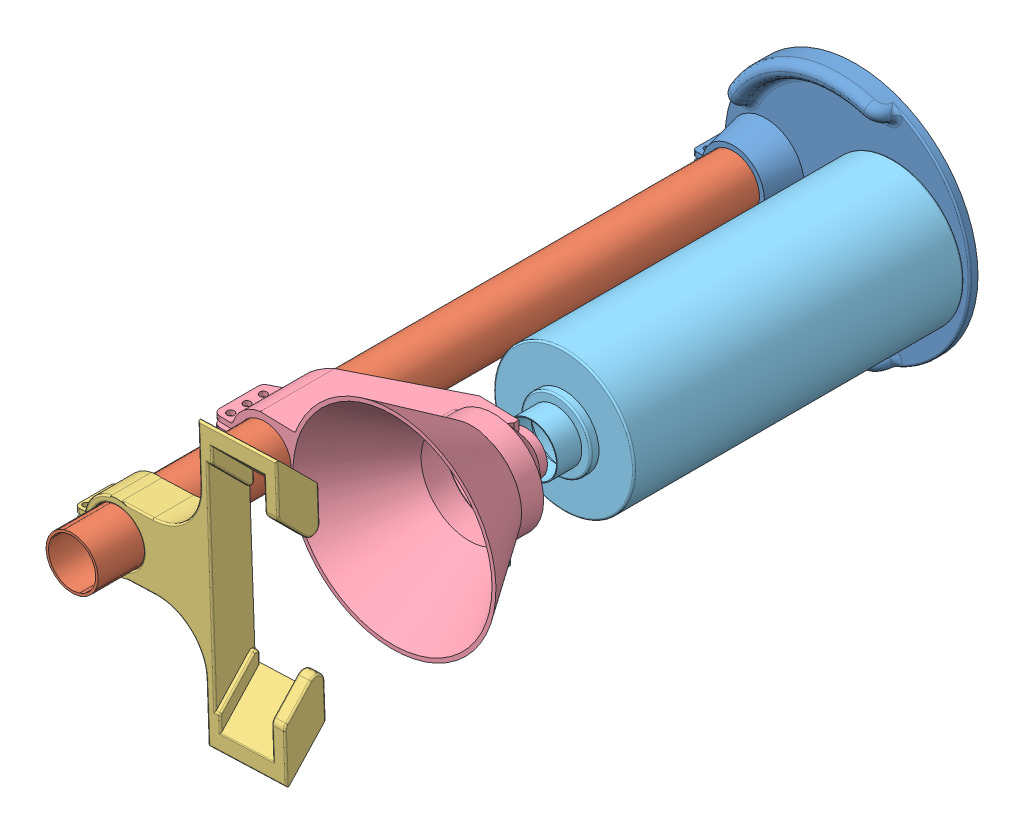
SolidWorks assembly 树脂沥干支架, configuration 默认. Lengths in mm.
Overall size (176.78 231.56 430).
6 component instances, 6 part files, 6 mates.
Components (placement in the parent):
- 底座-1: 底座 [默认] at (-38.7158 -17.6664 148.5) size (150.1 150 25.11)
- 管子-1: 管子 [默认] at (-88.7158 -17.6664 363.5) x (0.891054 -0.453896 0) z (0 0 1) size (32 32 430)
- 料槽放置-2-平-1: 料槽放置-2-平 [默认] at (-11.946 -14.8249 525.9527) x (-0.036989 0.999316 0) z (0.999316 0.036989 0) size (169.8 25.06 126.82)
- 漏斗-2-1: 漏斗-2 [默认] at (-10.3773 -19.7866 393.5703) x (-0.999634 0.027054 0) z (0.027054 0.999634 0) size (173.41 82 126.82)
- 一升瓶子-1: 一升瓶子 [默认] at (-10.3773 -19.7866 264.5) x (1 0 0) z (0 -1 0) size (86 222 86)
- 夹子2-1: 夹子2 [默认] at (-99.3405 -160.6541 304.5729) size (6.5 15 4)
Mates (geometry in assembly coordinates):
- 同心1: concentric aligned: cylinder of 底座-1 through (-88.7158 -17.6664 158.5) axis (0 0 -1) radius 16.1; cylinder of 管子-1 through (-88.7158 -17.6664 578.5) axis (0 0 -1) radius 16
- 重合1: coincident aligned: plane of 底座-1 through (-38.7158 -17.6664 148.5) normal (0 0 -1); plane of 管子-1 through (-88.7158 -17.6664 148.5) normal (0 0 -1)
- 同心2: concentric anti-aligned: cylinder of 管子-1 through (-88.7158 -17.6664 578.5) axis (0 0 -1) radius 16; cylinder of 料槽放置-2-平-1 through (-88.7158 -17.6664 525.9526) axis (0 0 1) radius 16.25
- 同心3: concentric anti-aligned: cylinder of 管子-1 through (-88.7158 -17.6664 578.5) axis (0 0 -1) radius 16; cylinder of 漏斗-2-1 through (-88.7158 -17.6664 500.5703) axis (0 0 1) radius 16.25
- 重合2: coincident anti-aligned: plane of 底座-1 through (-38.7158 -17.6664 153.5) normal (0 0 1); plane of 一升瓶子-1 through (32.6227 -19.7866 153.5) normal (0 0 -1)
- 同心4: concentric aligned: cylinder of 漏斗-2-1 through (-10.3773 -19.7866 378.5703) axis (0 0 1) radius 13; cylinder of 一升瓶子-1 through (-10.3773 -19.7866 301.4395) axis (0 0 1) radius 16
